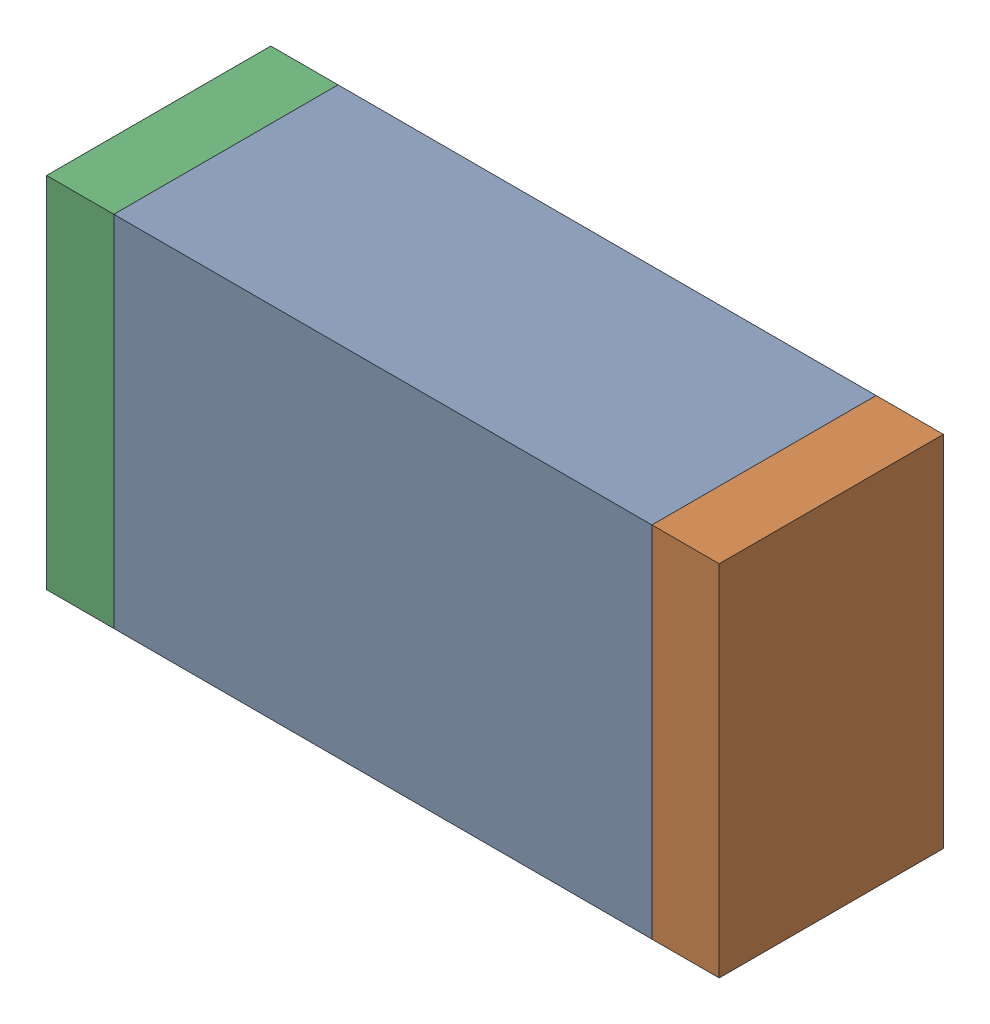
SolidWorks assembly C3, configuration Default. Lengths in mm.
Overall size (1.5 0.8 0.5).
6 component instances, 2 part files, 0 mates.
Components (placement in the parent):
- 836752368-1: 836752368 [Default] at (131.1 7.25 0) size (1.2 0.8 0.5)
  - Extruded-1: Extruded [Default] at origin size (1.2 0.8 0.5)
- 836752496-1: 836752496 [Default] at (131.775 7.25 0) size (0.15 0.8 0.5)
  - Extruded_2-1: Extruded_2 [Default] at origin size (0.15 0.8 0.5)
- 836752496-2: 836752496 [Default] at (130.425 7.25 0) size (0.15 0.8 0.5)
  - Extruded_2-1: Extruded_2 [Default] at origin size (0.15 0.8 0.5)
